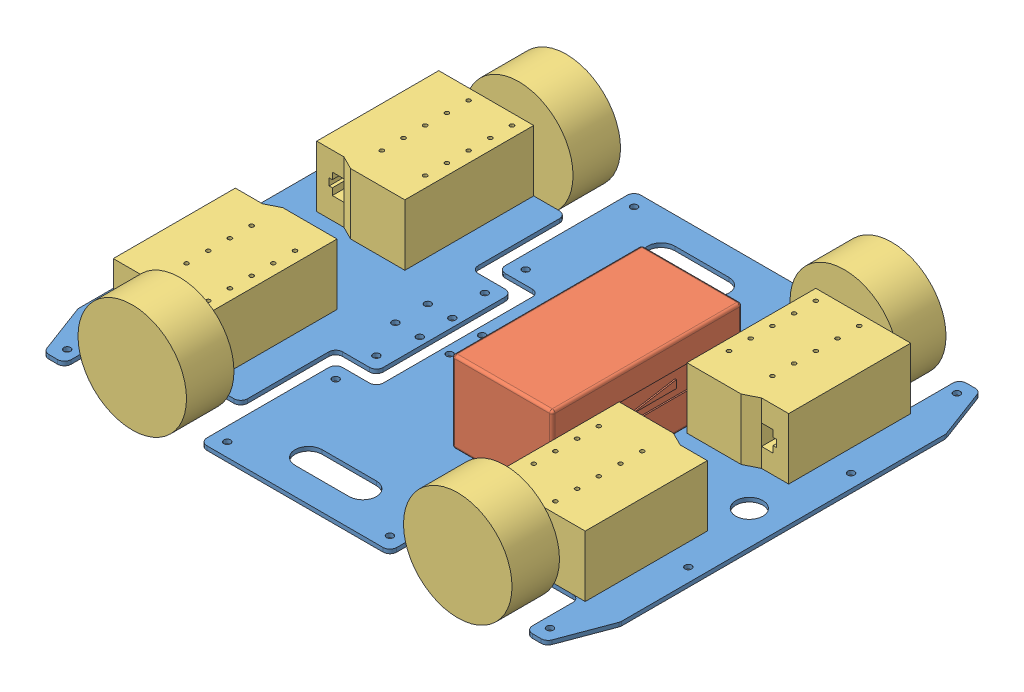
SolidWorks assembly 小车装配体, configuration 默认. Lengths in mm.
Overall size (400 80 320).
6 component instances, 3 part files, 13 mates.
Components (placement in the parent):
- 底板-1: 底板 [默认] at (-16.8434 -25.2913 400) size (400 3 320)
- 电池-1: 电池 [默认] at (46.9224 -22.2913 401.047) size (84 60 143.19)
- 电机及轮子-1: 电机及轮子 [默认] at (-155.8434 -22.2913 472.5) x (0 0 -1) z (1 0 0) size (135 80 94)
- 电机及轮子-2: 电机及轮子 [默认] at (122.1566 22.7087 472.5) x (0 0 -1) z (-1 0 0) size (135 80 94)
- 电机及轮子-3: 电机及轮子 [默认] at (122.1566 -22.2913 327.5) x (0 0 1) z (-1 0 0) size (135 80 94)
- 电机及轮子-4: 电机及轮子 [默认] at (-155.8434 22.7087 327.5) x (0 0 1) z (1 0 0) size (135 80 94)
Mates (geometry in assembly coordinates):
- 同心1: concentric: cylinder of assembly; cylinder of assembly; cylinder of 底板-1 through (-160.8434 -22.2913 512) axis (0 -1 0) radius 2.5; cylinder of 电机及轮子-1 through (-160.8434 22.7087 512) axis (0 -1 0) radius 1.5
- 同心2: concentric: cylinder of assembly; cylinder of assembly; cylinder of 底板-1 through (-128.8434 -22.2913 512) axis (0 -1 0) radius 2.5; cylinder of 电机及轮子-1 through (-128.8434 22.7087 512) axis (0 -1 0) radius 1.5
- 重合1: coincident: plane of assembly; plane of assembly; plane of 底板-1 through (-71.8434 -22.2913 355) normal (0 1 0); plane of 电机及轮子-1 through (-155.8434 -22.2913 472.5) normal (0 -1 0)
- 重合2: coincident: plane of assembly; plane of assembly; plane of 底板-1 through (-81.8434 -22.2913 245) normal (0 1 0); plane of 电池-1 through (46.9224 -22.2913 401.047) normal (0 -1 0)
- 同心3: concentric: cylinder of assembly; cylinder of assembly; cylinder of 底板-1 through (-128.8434 -22.2913 288) axis (0 -1 0) radius 2.5; cylinder of 电机及轮子-4 through (-128.8434 -22.2913 288) axis (0 1 0) radius 1.5
- 同心4: concentric: cylinder of assembly; cylinder of assembly; cylinder of 底板-1 through (-160.8434 -22.2913 288) axis (0 -1 0) radius 2.5; cylinder of 电机及轮子-4 through (-160.8434 -22.2913 288) axis (0 1 0) radius 1.5
- 重合3: coincident: plane of assembly; plane of assembly; plane of 底板-1 through (-71.8434 -22.2913 355) normal (0 1 0); plane of 电机及轮子-4 through (-155.8434 -22.2913 327.5) normal (0 -1 0)
- 同心6: concentric: cylinder of assembly; cylinder of assembly; cylinder of 底板-1 through (95.1566 -22.2913 288) axis (0 -1 0) radius 2.5; cylinder of 电机及轮子-3 through (95.1566 22.7087 288) axis (0 -1 0) radius 1.5
- 同心7: concentric: cylinder of assembly; cylinder of assembly; cylinder of 底板-1 through (127.1566 -22.2913 288) axis (0 -1 0) radius 2.5; cylinder of 电机及轮子-3 through (127.1566 22.7087 288) axis (0 -1 0) radius 1.5
- 重合4: coincident: plane of assembly; plane of assembly; plane of 底板-1 through (-81.8434 -22.2913 245) normal (0 1 0); plane of 电机及轮子-3 through (122.1566 -22.2913 327.5) normal (0 -1 0)
- 同心8: concentric: cylinder of assembly; cylinder of assembly; cylinder of 底板-1 through (95.1566 -22.2913 512) axis (0 -1 0) radius 2.5; cylinder of 电机及轮子-2 through (95.1566 -22.2913 512) axis (0 1 0) radius 1.5
- 同心9: concentric: cylinder of assembly; cylinder of assembly; cylinder of 底板-1 through (127.1566 -22.2913 512) axis (0 -1 0) radius 2.5; cylinder of 电机及轮子-2 through (127.1566 -22.2913 512) axis (0 1 0) radius 1.5
- 重合5: coincident: plane of assembly; plane of assembly; plane of 底板-1 through (-81.8434 -22.2913 245) normal (0 1 0); plane of 电机及轮子-2 through (122.1566 -22.2913 472.5) normal (0 -1 0)
